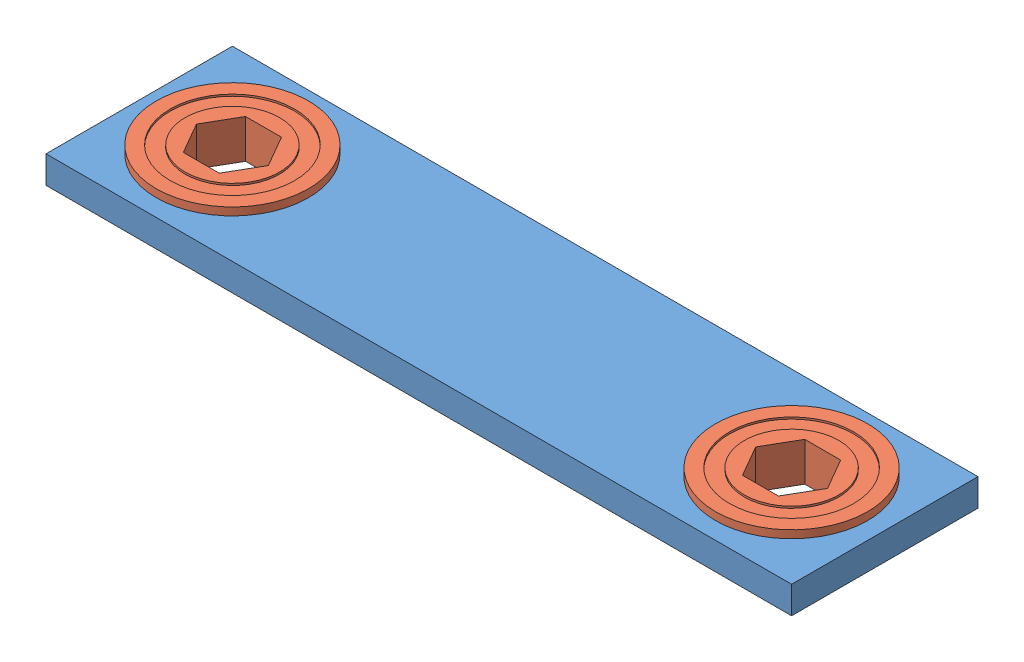
SolidWorks assembly intake arm with bearing, configuration Default. Lengths in mm.
Overall size (152.4 7.94 38.1).
3 component instances, 2 part files, 4 mates.
Components (placement in the parent):
- intake arm-1: intake arm [Default] at (153.6814 89.6919 120.1574) x (-1 0 0) z (0 0 1) size (152.4 5.59 38.1)
- Hex Bearing .5 in internal-2: Hex Bearing .5 in internal [Default] at (20.3314 83.3419 101.1074) size (31.12 7.94 31.12)
- Hex Bearing .5 in internal-3: Hex Bearing .5 in internal [Default] at (134.6314 83.3419 101.1074) size (31.12 7.94 31.12)
Mates (geometry in assembly coordinates):
- Concentric1: concentric anti-aligned: cylinder of intake arm-1 through (20.3314 89.6919 101.1074) axis (0 -1 0) radius 14.224; cylinder of Hex Bearing .5 in internal-2 through (20.3314 83.3419 101.1074) axis (0 1 0) radius 14.2748
- Coincident1: coincident aligned: plane of intake arm-1 through (153.6814 89.6919 120.1574) normal (0 1 0); circle of Hex Bearing .5 in internal-2
- Concentric2: concentric anti-aligned: cylinder of intake arm-1 through (134.6314 89.6919 101.1074) axis (0 -1 0) radius 14.224; cylinder of Hex Bearing .5 in internal-3 through (134.6314 83.3419 101.1074) axis (0 1 0) radius 14.2748
- Coincident2: coincident aligned: plane of intake arm-1 through (153.6814 89.6919 120.1574) normal (0 1 0); circle of Hex Bearing .5 in internal-3
